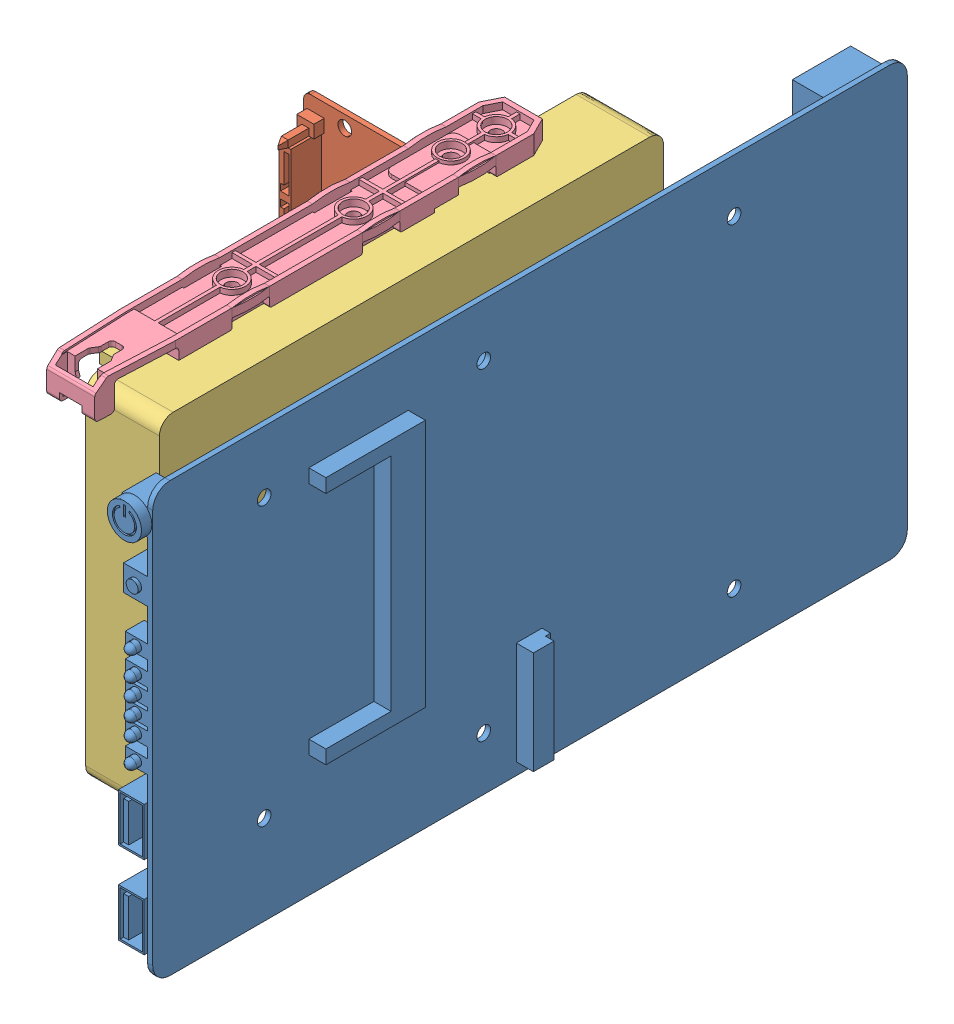
SolidWorks assembly 硬盘主板装配体, configuration 默认. Lengths in mm.
Overall size (141.5 125 224).
7 component instances, 4 part files, 9 mates.
Components (placement in the parent):
- 主板-1: 主板 [默认] at (-15.0423 -1.3933 223) size (24.5 125 224)
- 扩展板-1: 扩展板 [默认] at (-85.7923 -25.6433 151) size (131.5 58.5 12.5)
- 3_5寸硬盘整体-1: 3_5寸硬盘整体 [默认] at (-69.0923 -0.6433 230) x (0 0 -1) z (0 -1 0) size (147 26.5 102)
- 3_5寸硬盘整体-2: 3_5寸硬盘整体 [默认] at (-95.7923 -0.6433 230) x (0 0 -1) z (0 -1 0) size (147 26.5 102) (suppressed, hidden)
- 3_5寸硬盘整体-3: 3_5寸硬盘整体 [默认] at (-122.7923 -0.6433 230) x (0 0 -1) z (0 -1 0) size (147 26.5 102) (suppressed, hidden)
- 3_5寸硬盘整体-4: 3_5寸硬盘整体 [默认] at (-149.7923 -0.6433 230) x (0 0 -1) z (0 -1 0) size (147 26.5 102) (suppressed, hidden)
- 硬盘支架零件1-1: 硬盘支架零件1 [默认] at (-62.8423 45.8567 243.1) x (-1 0 0) z (0 1 0) size (17 132 10.5)
Mates (geometry in assembly coordinates):
- 重合1: coincident anti-aligned: plane of 主板-1 through (-20.0423 -28.3933 152.5) normal (0 0 -1); plane of 扩展板-1 through (-85.7923 -25.6433 152.5) normal (0 0 1)
- 重合2: coincident: plane of 主板-1 through (-20.0423 -39.8933 150.5) normal (0 1 0); plane of 扩展板-1 through (-20.0423 -39.8933 152.5) normal (0 -1 0)
- 重合3: coincident anti-aligned: plane of 主板-1 through (-20.0423 -1.3933 223) normal (-1 0 0); plane of 扩展板-1 through (-20.0423 3.6067 152.5) normal (1 0 0)
- 重合6: coincident anti-aligned: plane of 扩展板-1 through (-4.7923 -25.6433 156.5) normal (0 0 1); plane of 3_5寸硬盘整体-1 through (-42.5923 50.3567 156.5) normal (0 0 -1)
- 距离1: distance = 0.3 mm anti-aligned: plane of 扩展板-1 through (-65.7923 -18.1433 156.5) normal (-1 0 0); plane of 3_5寸硬盘整体-1 through (-66.0923 -38.6433 135.9027) normal (1 0 0)
- 重合8: coincident anti-aligned: plane of 扩展板-1 through (-67.2923 -5.6433 156.5) normal (0 -1 0); plane of 3_5寸硬盘整体-1 through (-66.0923 -5.6433 135.9027) normal (0 1 0)
- 重合10: coincident aligned: axis of 3_5寸硬盘整体-1 through (-62.8423 46.8567 286.6) axis (0 1 0); axis of 硬盘支架零件1-1 through (-62.8423 48.8567 286.6) axis (0 1 0)
- 重合11: coincident anti-aligned: axis of 3_5寸硬盘整体-1 through (-62.8423 46.8567 185) axis (0 1 0); axis of 硬盘支架零件1-1 through (-62.8423 55.3567 185) axis (0 -1 0)
- 重合12: coincident anti-aligned: plane of 3_5寸硬盘整体-1 through (-42.5923 50.3567 303.5) normal (0 1 0); plane of 硬盘支架零件1-1 through (-62.8423 50.3567 243.1) normal (0 -1 0)
